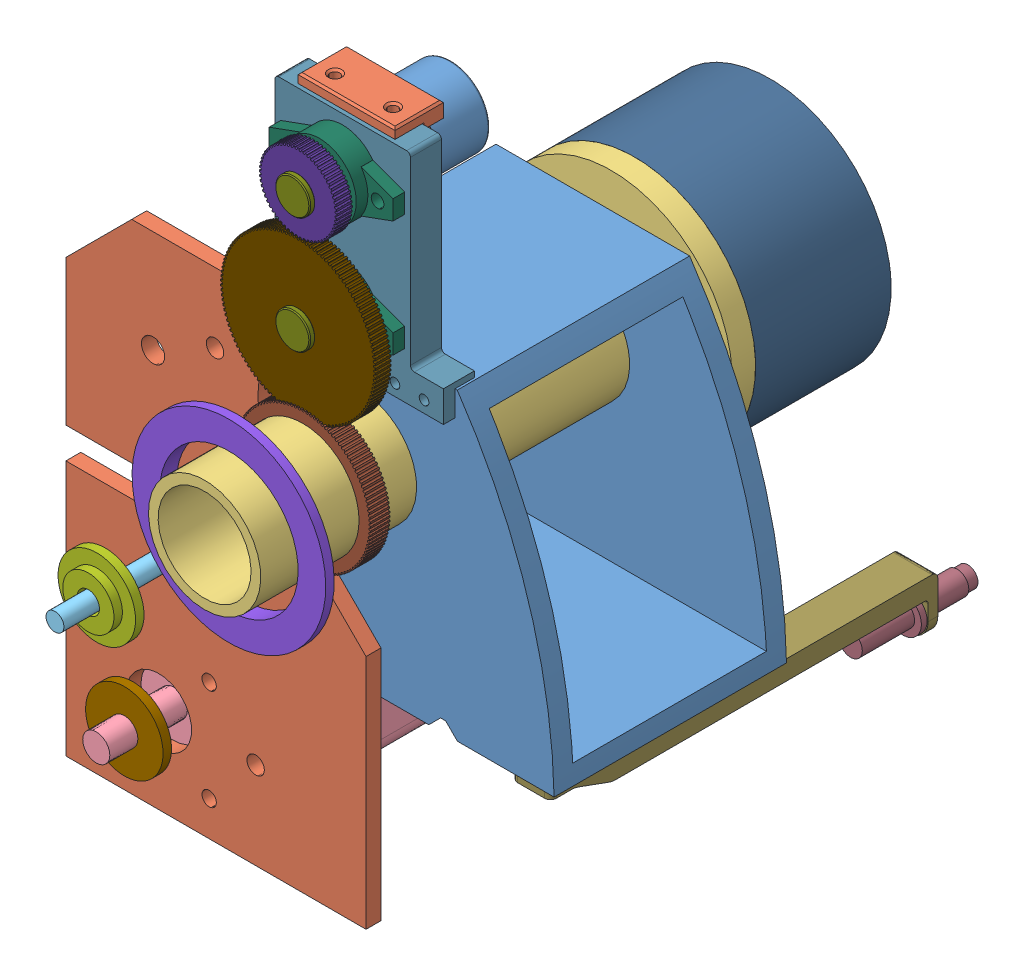
SolidWorks assembly motor_holder_assembly, configuration Default. Lengths in mm.
Overall size (244.4 383.2 314.68).
27 component instances, 20 part files, 29 mates.
Components (placement in the parent):
- spindel_holder-1: spindel_holder [Default] at (43.5148 19.3958 33.9726) size (150 157 126)
- panel-1: panel [Default] at (80.694 150.544 161.6726) x (-1 0 0) z (0 0 -1) size (211.23 273.55 7.7)
- spindel_tube-1: spindel_tube [Default] at (83.418 109.8065 24.4376) x (0.999015 0.044368 0) z (0 0 1) size (125 125 222)
- 3f_motor-1: 3f_motor [Default] at (-29.4675 -27.9725 153.9726) x (-1 0 0) z (0 0 -1) size (80 80 185)
- central_wheel-1: central_wheel [Default] at (-81.7524 19.6673 209.4309) x (-0.923728 -0.383049 0) z (0 0 -1) size (52.27 52.27 100)
  - short_root-1: short_root [Default] at (-99.1477 -13.1118 -33.7225) size (9.25 9.25 100)
  - rood_nut-1: rood_nut [Default] at (-99.1477 -13.1118 55.4583) x (0.999794 -0.02029 0) z (0 0 1) size (23.75 21.18 7)
  - rood_nut-2: rood_nut [Default] at (-99.1477 -13.1118 35.4583) x (0.999794 -0.02029 0) z (0 0 1) size (23.75 21.18 7)
  - round_part-1: round_part [Default] at (-101.9253 -14.2636 -7.7389) x (0 0 1) z (-0.923728 -0.383049 0) size (8.74 40 40)
- whell_spindel-1: whell_spindel [Default] at (107.8371 121.3102 221.9004) x (0 0 1) z (-0.904642 -0.426173 0) size (8.74 100 100)
- motor_whell-1: motor_whell [Default] at (-15.5258 -50.798 179.4891) x (0 0 1) z (-0.845729 -0.533613 0) size (8.74 40 40)
- part_hoder-1: part_hoder [Default] at (83.418 109.8065 -57.5624) x (0.993308 0.115499 0) z (0 0 1) size (125 125 70)
- spindel_wheel-1: spindel_wheel [Default] at (83.418 109.8065 183.7197) x (0 0 -1) z (0.99999 -0.004424 0) size (10 69.99 70)
- front_sensor_holder-1: front_sensor_holder [Default] at (161.5638 -14.9628 -5.8146) size (20 30 200)
- big_sensor-2: big_sensor [Default] at (171.5638 -13.1935 -11.0274) x (0.98769 0.156427 0) z (0 0 -1) size (19 19 60.5)
- gear_box_back-1: gear_box_back [Default] at (134.3104 202.5991 67.4754) x (0 1 0) z (0 0 1) size (163.01 105.62 82)
  - holder-1: holder [Default] at (12.8649 69.8201 86.4972) size (113 87 16)
  - wg_assembly-1: wg_assembly [Default] at (-22.7926 54.053 92.4972) x (0 0 1) z (0 1 0) size (33 38 64)
    - bearing_h-1: bearing_h [Default] at origin size (15 38 64)
    - roll_fixator-1: roll_fixator [Default] at (23 0 0) x (0 0 -1) z (1 0 0) size (18 18 33)
  - wg_assembly-2: wg_assembly [Default] at (37.2074 54.053 92.4972) x (0 0 1) z (0 1 0) size (33 38 64)
    - bearing_h-1: bearing_h [Default] at origin size (15 38 64)
    - roll_fixator-1: roll_fixator [Default] at (23 0 0) x (0 0 -1) z (1 0 0) size (18 18 33)
  - spindel_wheel_encoder-1: spindel_wheel_encoder [Default] at (37.2074 54.053 115.4972) x (0 0 -1) z (1 0 0) size (8 40 40)
  - spindel_wheel_encoder-80-1: spindel_wheel_encoder-80 [Default] at (-22.7926 54.053 107.4972) x (0 0 1) z (-0.913442 0.40697 0) size (8 79.99 79.99)
  - encoder-1: encoder [Default] at (37.2074 54.053 36.4972) size (40 40 59)
  - sensor_holder-1: sensor_holder [Default] at (39.0544 52.9619 99.9054) x (0 0 -1) z (-0.508605 -0.861 0) size (25.43 62.18 60.77)
Mates (geometry in assembly coordinates):
- Coincident1: coincident anti-aligned: plane of spindel_holder-1 through (-105.4888 1.2597 153.9726) normal (0 0 1); plane of panel-1 through (80.694 150.544 153.9726) normal (0 0 -1)
- Coincident2: coincident aligned: plane of spindel_holder-1 through (33.418 163.8065 153.9726) normal (0 1 0); plane of panel-1 through (94.0173 163.8065 153.9726) normal (0 1 0)
- Concentric1: concentric anti-aligned: cylinder of spindel_holder-1 through (83.418 109.8065 -46.0274) axis (0 0 1) radius 29; cylinder of spindel_tube-1 through (83.418 109.8065 234.4376) axis (0 0 -1) radius 29
- Совпадение1: coincident anti-aligned: plane of panel-1 through (80.694 150.544 153.9726) normal (0 0 -1); plane of 3f_motor-1 through (-29.4675 -27.9725 153.9726) normal (0 0 1)
- Концентричный1: concentric aligned: circle of panel-1; cylinder of 3f_motor-1 through (-12.9827 -49.1935 193.9726) axis (0 0 -1) radius 7
- Параллельность1: parallel: line of panel-1 through (94.0173 -93.1935 161.6726) axis (-1 0 0); plane of 3f_motor-1 through (27.0173 -89.1935 8.9726) normal (0 -1 0)
- Coincident3: coincident anti-aligned: plane of panel-1 through (80.694 150.544 153.9726) normal (0 0 -1); plane of central_wheel-1/rood_nut-1 through (14.8556 45.5341 153.9726) normal (0 0 1)
- Concentric2: concentric aligned: cylinder of spindel_tube-1 through (83.418 109.8065 234.4376) axis (0 0 -1) radius 29; cylinder of whell_spindel-1 through (83.418 109.8065 209.8329) axis (0 0 -1) radius 35.741
- Concentric3: concentric aligned: cylinder of 3f_motor-1 through (-12.9827 -49.1935 193.9726) axis (0 0 -1) radius 7; cylinder of motor_whell-1 through (-12.9827 -49.1935 167.4216) axis (0 0 -1) radius 5.741
- Concentric4: concentric anti-aligned: cylinder of spindel_tube-1 through (83.418 109.8065 12.4376) axis (0 0 1) radius 62.5; cylinder of part_hoder-1 through (83.418 109.8065 12.4376) axis (0 0 -1) radius 62.5
- Coincident4: coincident anti-aligned: plane of spindel_tube-1 through (83.418 109.8065 12.4376) normal (0 0 -1); plane of part_hoder-1 through (83.418 109.8065 12.4376) normal (0 0 1)
- Coincident6: coincident anti-aligned: plane of panel-1 through (80.694 150.544 161.6726) normal (0 0 1); plane of encoder_hoder-1 through (-29.2467 115.9861 161.6726) normal (0 0 -1)
- Coincident8: coincident anti-aligned: plane of encoder-1 through (-8.0558 107.8159 193.7197) normal (0 0 -1); plane of encoder_hoder-1 through (-29.2467 115.9861 216.6726) normal (0 0 1)
- Concentric5: concentric aligned: cylinder of encoder-1 through (-8.0558 107.8159 188.7197) axis (0 0 1) radius 10; cylinder of encoder_hoder-1 through (-6.5858 107.1077 196.6726) axis (0 0 1) radius 9.9133
- Coincident9: coincident anti-aligned: plane of panel-1 through (-26.9827 163.8065 153.9726) normal (-0.707107 0.707107 0); plane of encoder_hoder-1 through (-62.0538 128.7354 151.6726) normal (0.707107 -0.707107 0)
- Coincident10: coincident anti-aligned: plane of panel-1 through (94.0173 163.8065 153.9726) normal (0 1 0); plane of encoder_hoder-1 through (-26.9827 163.8065 151.6726) normal (0 -1 0)
- Concentric6: concentric anti-aligned: cylinder of spindel_tube-1 through (83.418 109.8065 234.4376) axis (0 0 -1) radius 29; cylinder of spindel_wheel-1 through (83.418 109.8065 173.7197) axis (0 0 1) radius 29
- Concentric7: concentric anti-aligned: cylinder of encoder-1 through (-8.0558 107.8159 173.7197) axis (0 0 1) radius 3; cylinder of spindel_wheel_encoder-1 through (-8.0558 107.8159 181.7197) axis (0 0 -1) radius 6
- Coincident11: coincident aligned: circle of encoder-1; plane of spindel_wheel_encoder-1 through (-8.0558 107.8159 173.7197) normal (0 0 -1)
- Coincident12: coincident aligned: plane of spindel_wheel-1 through (83.418 109.8065 173.7197) normal (0 0 -1); plane of spindel_wheel_encoder-1 through (-8.0558 107.8159 173.7197) normal (0 0 -1)
- Coincident13: coincident anti-aligned: plane of spindel_holder-1 through (33.418 6.8065 153.9726) normal (0 -1 0); plane of front_sensor_holder-1 through (181.5638 6.8065 153.9726) normal (0 1 0)
- Concentric8: concentric aligned: cylinder of front_sensor_holder-1 through (171.5638 -13.1935 -61.0274) axis (0 0 1) radius 6.5; cylinder of big_sensor-2 through (171.5638 -13.1935 -66.0274) axis (0 0 1) radius 6
- Concentric9: concentric aligned: cylinder of spindel_wheel_encoder-1 through (-8.0558 107.8159 181.7197) axis (0 0 -1) radius 20; cylinder of belt_encoder-1 through (-6.5858 107.1077 206.6726) axis (0 0 -1) radius 35
- Coincident14: coincident aligned: plane of spindel_wheel_encoder-1 through (-8.0558 107.8159 181.7197) normal (0 0 1); plane of belt_encoder-1 through (-6.5858 107.1077 206.6726) normal (0 0 1)
- Concentric10: concentric anti-aligned: cylinder of spindel_wheel-1 through (83.418 109.8065 173.7197) axis (0 0 1) radius 35; cylinder of belt_encoder-1 through (83.418 109.8065 206.6726) axis (0 0 -1) radius 35
- Coincident15: coincident aligned: plane of spindel_holder-1 through (-105.4888 1.2597 153.9726) normal (0 0 1); plane of front_sensor_holder-1 through (181.5638 3.8065 153.9726) normal (0 0 1)
- Coincident16: coincident aligned: plane of front_sensor_holder-1 through (181.5638 -23.1935 -41.0274) normal (0 0 1); circle of big_sensor-2
- Coincident17: coincident anti-aligned: plane of spindel_holder-1 through (33.418 163.8065 153.9726) normal (0 1 0); plane of gear_box_back-1/holder-1 through (112.2575 163.8065 143.9726) normal (0 -1 0)
- Coincident18: coincident anti-aligned: plane of spindel_holder-1 through (-105.4888 1.2597 153.9726) normal (0 0 1); plane of gear_box_back-1/holder-1 through (64.4903 215.464 153.9726) normal (0 0 -1)
